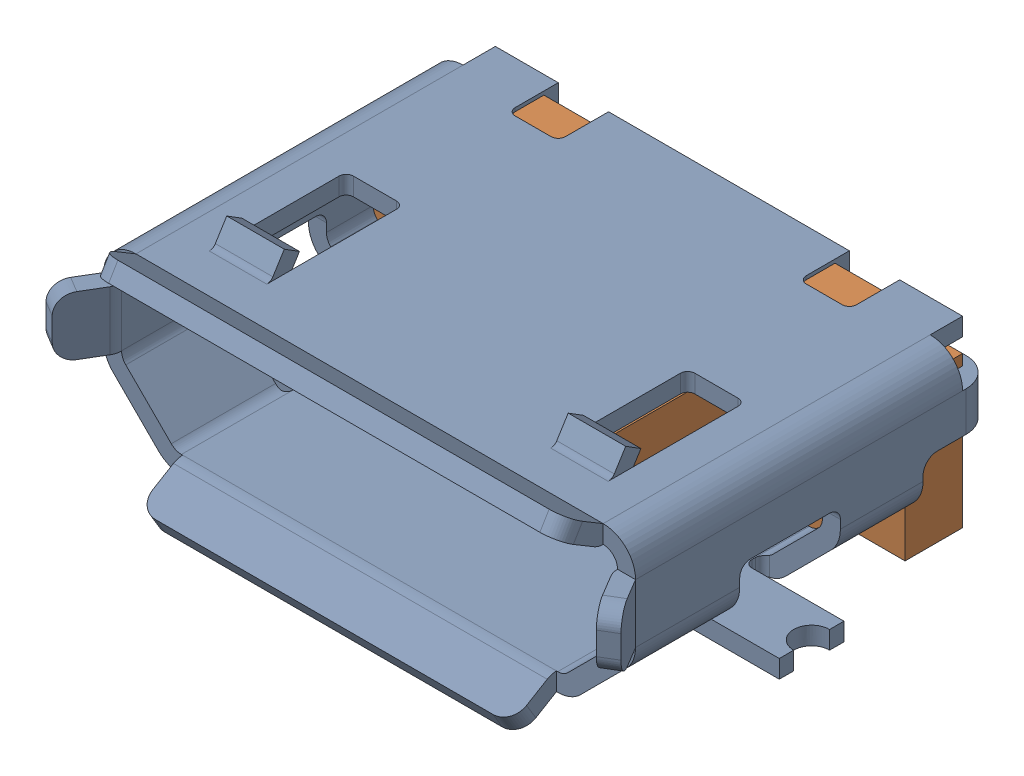
SolidWorks assembly micro usb, configuration Predeterminado. Lengths in mm.
Overall size (8.01 3.25 5.93).
7 component instances, 3 part files, 0 mates.
Components (placement in the parent):
- micro usb shell-1: micro usb shell [Predeterminado] at origin size (8.01 2.95 5.63)
- micro usb internal-1: micro usb internal [Predeterminado] at (0 -0.25 0) size (6.9 2.9 4)
- micro usb contact-1: micro usb contact [Predeterminado] at (1.3 -0.25 -0.1) size (0.2 1.3 4.4)
- micro usb contact-2: micro usb contact [Predeterminado] at (0.65 -0.25 -0.1) size (0.2 1.3 4.4)
- micro usb contact-3: micro usb contact [Predeterminado] at (0 -0.25 -0.1) size (0.2 1.3 4.4)
- micro usb contact-4: micro usb contact [Predeterminado] at (-0.65 -0.25 -0.1) size (0.2 1.3 4.4)
- micro usb contact-5: micro usb contact [Predeterminado] at (-1.3 -0.25 -0.1) size (0.2 1.3 4.4)
